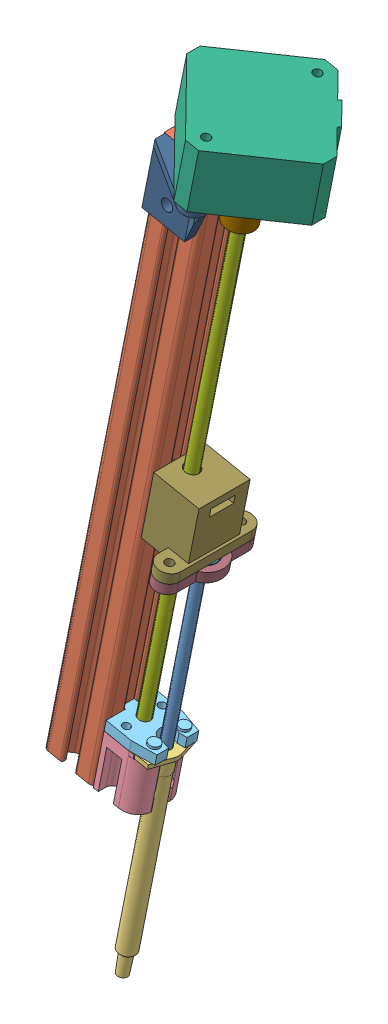
SolidWorks assembly syringeassembly, configuration Default. Lengths in mm.
Overall size (105.47 327.36 60.49).
14 component instances, 13 part files, 31 mates.
Components (placement in the parent):
- syringeplunger-1: syringeplunger [Default] at (27.1465 10.9646 0) x (0 0 -1) z (0.980654 -0.195748 0) size (10.2 79.6 10.2)
- AluminumExtrusion-1: AluminumExtrusion [9inches] at (22.9563 115.0317 -0.005) x (0 0 -1) z (-0.195748 -0.980654 0) size (19.96 19.96 234.6)
- 1mlsyringe-1: 1mlsyringe [Default] at (13.0357 -59.7272 0) x (0.980654 -0.195748 0) z (0 0 1) size (10.21 87.13 19.02)
- syringeholderbottom-1: syringeholderbottom [Default] at (13.697 17.6605 0) x (0 0 -1) z (-0.195748 -0.980654 0) size (19.95 18.23 21.7)
- syringeholdertop-2: syringeholdertop [Default] at (14.0415 19.3865 0) x (0 0 1) z (0.195748 0.980654 0) size (19.95 23.86 7)
- smallstepper-1: smallstepper [Default] at (65.5995 251.6269 0) x (0.693427 -0.138415 0.707107) z (0.693427 -0.138415 -0.707107) size (42.17 36 43.37)
- Part3^syringeassembly-1: Part3^syringeassembly [Default] at (19.403 20.1925 0) x (0.919988 -0.183638 0.346264) z (0.195748 0.980654 0) size (4.66 4.66 200) (virtual)
- Part2^syringeassembly-1: Part2^syringeassembly [Default] at (37.8153 112.434 0) x (0.849271 -0.169523 0.5) z (-0.195748 -0.980654 0) size (9.33 10.77 3.2) (virtual)
- Part2^syringeassembly-2: Part2^syringeassembly [Default] at (34.2527 94.5861 0) x (0.849271 -0.169523 -0.5) z (-0.195748 -0.980654 0) size (9.33 10.77 3.2) (virtual)
- Part6^syringeassembly-1: Part6^syringeassembly [Default] at (104.2294 199.0481 -44.0705) x (0.918897 -0.183421 -0.349263) z (0.195748 0.980654 0) size (11.17 11.17 15) (virtual)
- Part7^syringeassembly-1: Part7^syringeassembly [Default] at (120.3811 216.8304 -24.4695) x (-0.980654 0.195748 0) z (0.195748 0.980654 0) size (28.3 18.33 26.2) (virtual)
- MirrorPart7^syringeassembly-3: MirrorPart7^syringeassembly [Default] at (120.3811 216.8304 24.4695) x (-0.980654 0.195748 0) z (-0.195748 -0.980654 0) size (28.3 18.33 26.2) (virtual)
- pistonholder-1: pistonholder [Default] at (28.5075 91.8579 -0.01) x (0.980654 -0.195748 0) z (0.195748 0.980654 0) size (24 36.95 25)
- Part1^syringeassembly-1: Part1^syringeassembly [Default] at (28.5075 91.8579 -0.01) x (-0.980654 0.195748 0) z (-0.195748 -0.980654 0) size (12.52 36.95 4) (virtual)
Mates (geometry in assembly coordinates):
- Concentric1: concentric aligned: cylinder of syringeplunger-1 through (42.4148 87.4557 0) axis (-0.195748 -0.980654 0) radius 2; cylinder of 1mlsyringe-1 through (26.5815 8.1341 0) axis (-0.195748 -0.980654 0) radius 3.325
- LimitDistance1: limit distance = 72.3064 mm anti-aligned: plane of syringeplunger-1 through (42.4148 87.4557 0) normal (-0.195748 -0.980654 0); plane of 1mlsyringe-1 through (28.261 16.5481 0) normal (0.195748 0.980654 0)
- Parallel1: parallel aligned: plane of syringeplunger-1 through (27.1465 10.9646 0) normal (0.980654 -0.195748 0); plane of AluminumExtrusion-1 through (9.782 -1.9526 -7.9784) normal (0.980654 -0.195748 0)
- Coincident8: coincident anti-aligned: plane of AluminumExtrusion-1 through (9.782 -1.9526 7.9684) normal (0.980654 -0.195748 0); plane of syringeholderbottom-1 through (9.782 -1.9526 9.975) normal (-0.980654 0.195748 0)
- Coincident9: coincident aligned: plane of AluminumExtrusion-1 through (7.8142 -1.5598 9.975) normal (0 0 1); plane of syringeholderbottom-1 through (9.782 -1.9526 9.975) normal (0 0 1)
- Concentric2: concentric anti-aligned: cylinder of 1mlsyringe-1 through (26.5815 8.1341 0) axis (-0.195748 -0.980654 0) radius 3.325; cylinder of syringeholderbottom-1 through (24.0015 -4.7909 0) axis (0.195748 0.980654 0) radius 3.325
- Parallel3: parallel aligned: plane of AluminumExtrusion-1 through (7.8142 -1.5598 9.975) normal (0 0 1); plane of 1mlsyringe-1 through (25.6623 17.0668 9.51) normal (0 0 1)
- Coincident11: coincident anti-aligned: plane of 1mlsyringe-1 through (27.9165 14.8222 0) normal (-0.195748 -0.980654 0); plane of syringeholderbottom-1 through (23.5035 15.703 -3.3372) normal (0.195748 0.980654 0)
- Coincident15: coincident anti-aligned: plane of AluminumExtrusion-1 through (9.782 -1.9526 7.9684) normal (0.980654 -0.195748 0); plane of syringeholdertop-2 through (14.8245 23.3091 -9.975) normal (-0.980654 0.195748 0)
- Coincident16: coincident aligned: plane of AluminumExtrusion-1 through (7.8142 -1.5598 9.975) normal (0 0 1); plane of syringeholdertop-2 through (14.8245 23.3091 9.975) normal (0 0 1)
- Coincident17: coincident anti-aligned: plane of 1mlsyringe-1 through (28.261 16.5481 0) normal (0.195748 0.980654 0); plane of syringeholdertop-2 through (28.261 16.5481 0) normal (-0.195748 -0.980654 0)
- Concentric3: concentric anti-aligned: cylinder of smallstepper-1 through (58.5526 216.3234 0) axis (0.195748 0.980654 0) radius 2.5; cylinder of Part3^syringeassembly-1 through (58.5526 216.3234 0) axis (-0.195748 -0.980654 0) radius 2.33
- Coincident18: coincident anti-aligned: plane of smallstepper-1 through (58.5526 216.3234 0) normal (-0.195748 -0.980654 0); plane of Part3^syringeassembly-1 through (58.5526 216.3234 0) normal (0.195748 0.980654 0)
- Parallel4: parallel aligned: plane of AluminumExtrusion-1 through (6.448 -1.2871 1.0835) normal (-0.195748 -0.980654 0); plane of Part3^syringeassembly-1 through (19.403 20.1925 0) normal (-0.195748 -0.980654 0)
- Coincident22: coincident aligned: plane of AluminumExtrusion-1 through (6.448 -1.2871 1.0835) normal (-0.195748 -0.980654 0); plane of syringeholderbottom-1 through (19.5886 -3.9101 -3.3372) normal (-0.195748 -0.980654 0)
- Concentric5: concentric anti-aligned: cylinder of Part3^syringeassembly-1 through (58.5526 216.3234 0) axis (-0.195748 -0.980654 0) radius 2.33; cylinder of Part2^syringeassembly-1 through (37.1889 109.2959 0) axis (0.195748 0.980654 0) radius 2.075
- Concentric6: concentric anti-aligned: cylinder of Part3^syringeassembly-1 through (58.5526 216.3234 0) axis (-0.195748 -0.980654 0) radius 2.33; cylinder of Part2^syringeassembly-2 through (33.6263 91.448 0) axis (0.195748 0.980654 0) radius 2.075
- Coincident29: coincident aligned: plane of Part2^syringeassembly-1 through (39.8301 108.7687 4.665) normal (0 0 1); plane of Part2^syringeassembly-2 through (36.2675 90.9207 4.665) normal (0 0 1)
- Distance4: distance = 15 mm anti-aligned: plane of Part2^syringeassembly-2 through (34.2527 94.5861 0) normal (0.195748 0.980654 0); plane of Part2^syringeassembly-1 through (37.1889 109.2959 0) normal (-0.195748 -0.980654 0)
- Parallel7: parallel anti-aligned: plane of AluminumExtrusion-1 through (7.8142 -1.5598 -9.985) normal (0 0 -1); plane of Part2^syringeassembly-1 through (39.8301 108.7687 4.665) normal (0 0 1)
- Concentric7: concentric anti-aligned: cylinder of syringeholdertop-2 through (16.8896 7.6009 0) axis (0.195748 0.980654 0) radius 2.375; cylinder of Part3^syringeassembly-1 through (58.5526 216.3234 0) axis (-0.195748 -0.980654 0) radius 2.33
- Concentric8: concentric aligned: cylinder of Part3^syringeassembly-1 through (58.5526 216.3234 0) axis (-0.195748 -0.980654 0) radius 2.33; cylinder of Part6^syringeassembly-1 through (59.9228 223.188 0) axis (-0.195748 -0.980654 0) radius 5.584
- Coincident39: coincident anti-aligned: plane of smallstepper-1 through (58.5526 216.3234 0) normal (-0.195748 -0.980654 0); plane of Part6^syringeassembly-1 through (58.5526 216.3234 0) normal (0.195748 0.980654 0)
- Parallel10: parallel aligned: plane of AluminumExtrusion-1 through (7.8142 -1.5598 9.975) normal (0 0 1); plane of smallstepper-1 through (58.4533 229.1918 27.2024) normal (0 0 1)
- Coincident44: coincident anti-aligned: plane of AluminumExtrusion-1 through (7.8142 -1.5598 9.975) normal (0 0 1); plane of Part7^syringeassembly-1 through (49.4475 204.2726 9.975) normal (0 0 -1)
- Coincident45: coincident anti-aligned: plane of AluminumExtrusion-1 through (2.4565 -0.4903 8.4464) normal (-0.980654 0.195748 0); plane of Part7^syringeassembly-1 through (43.5636 205.447 8.1416) normal (0.980654 -0.195748 0)
- Coincident46: coincident anti-aligned: plane of smallstepper-1 through (61.019 228.6796 0) normal (-0.195748 -0.980654 0); plane of Part7^syringeassembly-1 through (120.3811 216.8304 -24.4695) normal (0.195748 0.980654 0)
- Coincident50: coincident anti-aligned: plane of AluminumExtrusion-1 through (52.3705 228.7744 1.0835) normal (0.195748 0.980654 0); plane of smallstepper-1 through (60.7058 227.1106 0) normal (-0.195748 -0.980654 0)
- Coincident51: coincident anti-aligned: plane of AluminumExtrusion-1 through (9.782 -1.9526 -7.9784) normal (0.980654 -0.195748 0); plane of pistonholder-1 through (33.4012 116.3742 2.3858) normal (-0.980654 0.195748 0)
- Coincident52: coincident aligned: plane of AluminumExtrusion-1 through (7.8142 -1.5598 -9.985) normal (0 0 -1); plane of pistonholder-1 through (33.4012 116.3742 -9.985) normal (0 0 -1)
- Coincident53: coincident anti-aligned: plane of Part2^syringeassembly-1 through (37.8153 112.434 0) normal (0.195748 0.980654 0); plane of pistonholder-1 through (87.2403 102.5683 4.74) normal (-0.195748 -0.980654 0)
